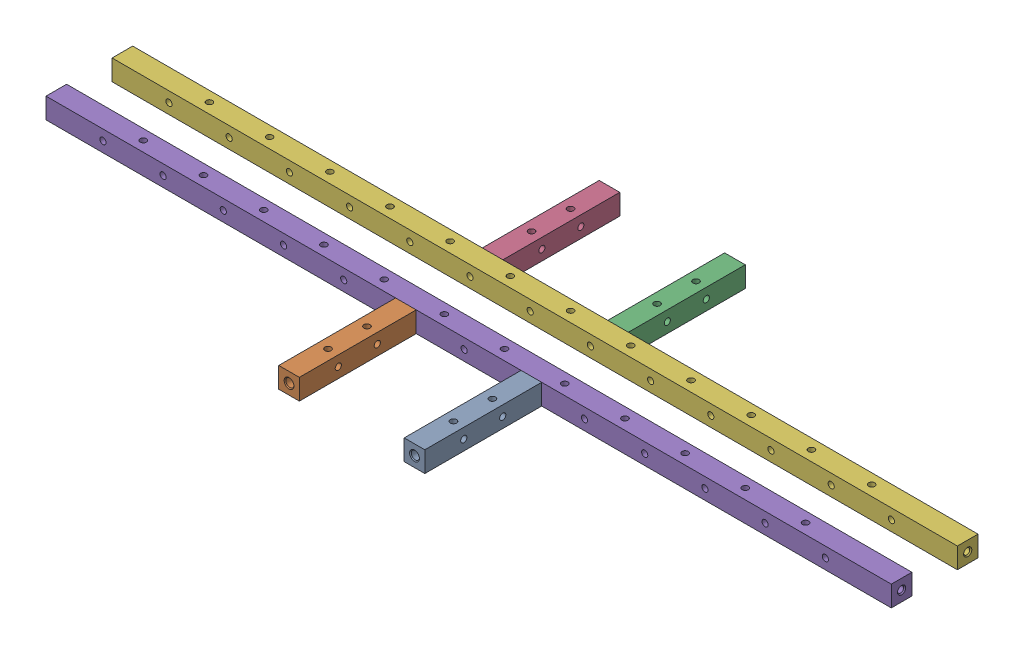
SolidWorks assembly frame_rectangular_assembly, configuration Default. Lengths in mm.
Overall size (520.7 12.7 197.4).
6 component instances, 2 part files, 13 mates.
Components (placement in the parent):
- barstock support_short-1: barstock support_short [Default] at (38.6418 6.85 98.7) x (0 0 -1) z (1 0 0) size (72 12.7 12.7)
- barstock support_short-2: barstock support_short [Default] at (-38.6418 6.85 98.7) x (0 0 -1) z (1 0 0) size (72 12.7 12.7)
- barstock support_short-3: barstock support_short [Default] at (38.6418 6.85 -98.7) x (0 0 1) z (-1 0 0) size (72 12.7 12.7)
- barstock support_short-4: barstock support_short [Default] at (-38.6418 6.85 -26.7) x (0 0 -1) z (1 0 0) size (72 12.7 12.7)
- barstock support_long-1: barstock support_long [Default] at (-260.35 6.85 20.35) size (520.7 12.7 12.7)
- barstock support_long-2: barstock support_long [Default] at (-260.35 6.85 -20.35) size (520.7 12.7 12.7)
Mates (geometry in assembly coordinates):
- Coincident19: coincident anti-aligned: plane of barstock support_long-1 through (260.35 0.5 26.7) normal (0 0 1); plane of barstock support_short-1 through (38.6418 6.85 26.7) normal (0 0 -1)
- Coincident21: coincident aligned: plane of barstock support_long-1 through (260.35 13.2 14) normal (0 1 0); plane of barstock support_short-1 through (32.2918 13.2 26.7) normal (0 1 0)
- Coincident54: coincident aligned: plane of barstock support_short-3 through (32.2918 0.5 -26.7) normal (-1 0 0); plane of barstock support_short-1 through (32.2918 0.5 26.7) normal (-1 0 0)
- Coincident17: coincident anti-aligned: plane of barstock support_long-1 through (260.35 0.5 26.7) normal (0 0 1); plane of barstock support_short-2 through (-38.6418 6.85 26.7) normal (0 0 -1)
- Coincident18: coincident aligned: plane of barstock support_long-1 through (260.35 13.2 14) normal (0 1 0); plane of barstock support_short-2 through (-44.9918 13.2 26.7) normal (0 1 0)
- Coincident55: coincident aligned: plane of barstock support_short-4 through (-32.2918 0.5 -98.7) normal (1 0 0); plane of barstock support_short-2 through (-32.2918 0.5 26.7) normal (1 0 0)
- Coincident15: coincident anti-aligned: plane of barstock support_long-2 through (260.35 0.5 -26.7) normal (0 0 -1); plane of barstock support_short-3 through (38.6418 6.85 -26.7) normal (0 0 1)
- Coincident16: coincident aligned: plane of barstock support_long-2 through (260.35 13.2 -26.7) normal (0 1 0); plane of barstock support_short-3 through (44.9918 13.2 -26.7) normal (0 1 0)
- Coincident13: coincident aligned: plane of barstock support_long-2 through (260.35 0.5 -26.7) normal (0 -1 0); plane of barstock support_short-4 through (-44.9918 0.5 -98.7) normal (0 -1 0)
- Coincident14: coincident anti-aligned: plane of barstock support_long-2 through (260.35 0.5 -26.7) normal (0 0 -1); plane of barstock support_short-4 through (-38.6418 6.85 -26.7) normal (0 0 1)
- Distance1: distance = 28 mm anti-aligned: plane of barstock support_long-1 through (260.35 0.5 14) normal (0 0 -1); plane of barstock support_long-2 through (260.35 0.5 -14) normal (0 0 1)
- Coincident84: coincident aligned: plane of barstock support_long-2 through (260.35 13.2 -26.7) normal (0 1 0); plane of barstock support_long-1 through (260.35 13.2 14) normal (0 1 0)
- Coincident86: coincident aligned: plane of barstock support_long-2 through (260.35 6.85 -20.35) normal (1 0 0); plane of barstock support_long-1 through (260.35 6.85 20.35) normal (1 0 0)
